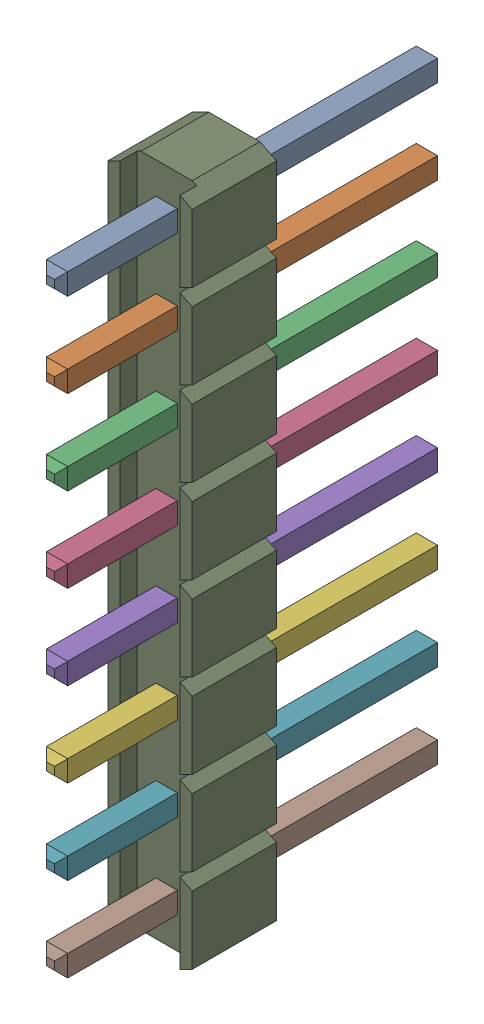
SolidWorks assembly 1-10, configuration 默认. Lengths in mm.
Overall size (2.54 20.32 11.54).
9 component instances, 9 part files, 0 mates.
Components (placement in the parent):
- Header8_2.54mm_RGB255-1: Header8_2.54mm_RGB255 [默认] at (21.3613 10.3123 -1.2168) x (0 -1 0) z (1 0 0) size (0.64 11.54 0.64)
- Header8_2.54mm_RGB255-11-1: Header8_2.54mm_RGB255-11 [默认] at (21.3613 10.3123 -1.2168) x (0 -1 0) z (1 0 0) size (0.64 11.54 0.64)
- Header8_2.54mm_RGB255-12-1: Header8_2.54mm_RGB255-12 [默认] at (21.3613 10.3123 -1.2168) x (0 -1 0) z (1 0 0) size (0.64 11.54 0.64)
- Header8_2.54mm_RGB255-13-1: Header8_2.54mm_RGB255-13 [默认] at (21.3613 10.3123 -1.2168) x (0 -1 0) z (1 0 0) size (0.64 11.54 0.64)
- Header8_2.54mm_RGB255-14-1: Header8_2.54mm_RGB255-14 [默认] at (21.3613 10.3123 -1.2168) x (0 -1 0) z (1 0 0) size (0.64 11.54 0.64)
- Header8_2.54mm_RGB255-15-1: Header8_2.54mm_RGB255-15 [默认] at (21.3613 10.3123 -1.2168) x (0 -1 0) z (1 0 0) size (0.64 11.54 0.64)
- Header8_2.54mm_RGB255-16-1: Header8_2.54mm_RGB255-16 [默认] at (21.3613 10.3123 -1.2168) x (0 -1 0) z (1 0 0) size (0.64 11.54 0.64)
- Header8_2.54mm_RGB255-17-1: Header8_2.54mm_RGB255-17 [默认] at (21.3613 10.3123 -1.2168) x (0 -1 0) z (1 0 0) size (0.64 11.54 0.64)
- Header8_2.54mm_RGB255-18-1: Header8_2.54mm_RGB255-18 [默认] at (21.3613 10.3123 -1.2168) x (0 -1 0) z (1 0 0) size (20.32 2.54 2.54)
